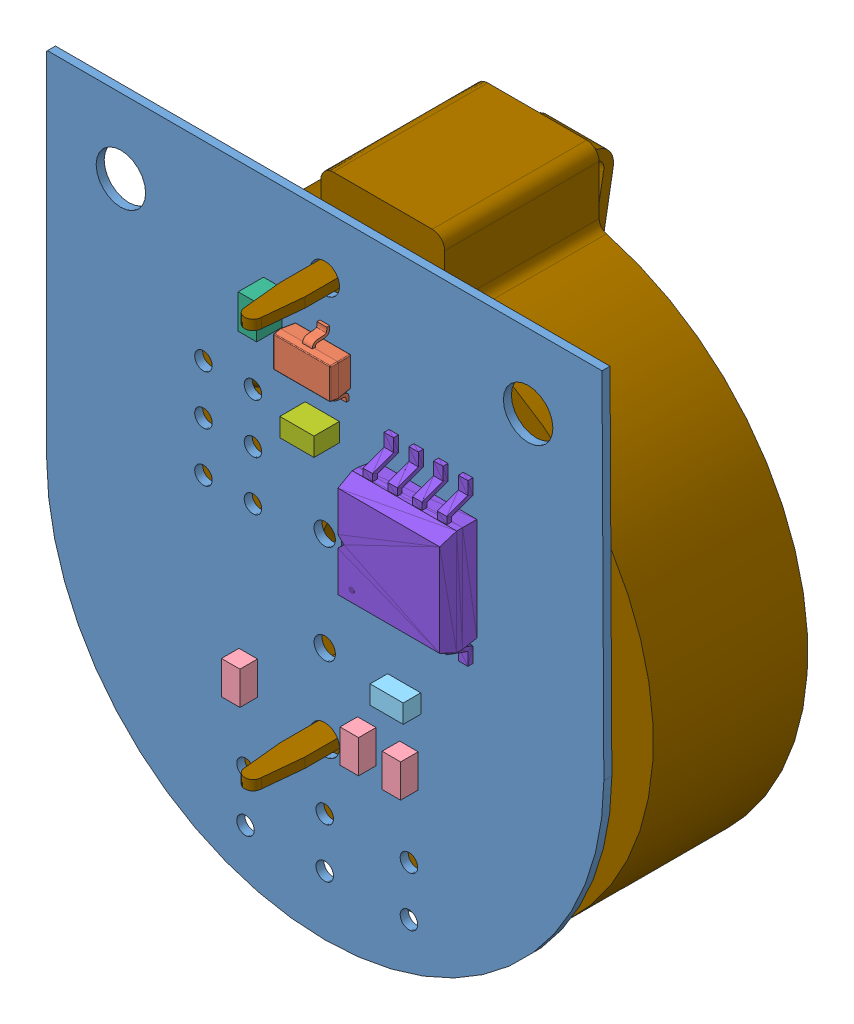
SolidWorks assembly Flashlight PCB 2, configuration Default. Lengths in mm.
Overall size (33.81 35.83 17.34).
27 component instances, 9 part files, 0 mates.
Components (placement in the parent):
- Board-1: Board [Default] at origin size (28.59 32.39 0.41)
- U1-1: U1 [Default] at origin size (3.01 2.91 1.23)
  - SOT23-3-1: SOT23-3 [Default] at (15.3909 26.7763 0) x (0 -1 0) z (0 0 1) size (2.91 3.01 1.23)
  - 4438511424-1: 4438511424 [Default] at (15.494 27.051 0) size (0.25 0.25 0.25)
    - Extruded-1: Extruded [Default] at origin size (0.25 0.25 0.25)
- R3-1: R3 [Default] at origin size (0.95 1.7 0.9)
  - 4438511040-1: 4438511040 [Default] at (19.685 10.656 0) size (0.95 1.7 0.9)
    - Extruded_2-1: Extruded_2 [Default] at origin size (0.95 1.7 0.9)
- R2-1: R2 [Default] at origin size (0.95 1.7 0.9)
  - 4438511040-1: 4438511040 [Default] at (17.526 10.656 0) size (0.95 1.7 0.9)
    - Extruded_2-1: Extruded_2 [Default] at origin size (0.95 1.7 0.9)
- R1-1: R1 [Default] at origin size (0.95 1.7 0.9)
  - 4438511040-1: 4438511040 [Default] at (11.442 10.656 0) size (0.95 1.7 0.9)
    - Extruded_2-1: Extruded_2 [Default] at origin size (0.95 1.7 0.9)
- R4-1: R4 [Default] at origin size (1.7 0.95 0.9)
  - 4438510848-1: 4438510848 [Default] at (19.443 13.716 0) size (1.7 0.95 0.9)
    - Extruded_3-1: Extruded_3 [Default] at origin size (1.7 0.95 0.9)
- C2-1: C2 [Default] at origin size (0.95 1.75 1.3)
  - 4438511232-1: 4438511232 [Default] at (12.7 27.748 0) size (0.95 1.75 1.3)
    - Extruded_4-1: Extruded_4 [Default] at origin size (0.95 1.75 1.3)
- C1-1: C1 [Default] at origin size (1.75 0.95 1.3)
  - 4438510656-1: 4438510656 [Default] at (15.24 23.684 0) size (1.75 0.95 1.3)
    - Extruded_5-1: Extruded_5 [Default] at origin size (1.75 0.95 1.3)
- ATTiny85-1: ATTiny85 [Default] at origin size (8.25 5.36 2.16)
  - 8S2-1: 8S2 [Default] at (20.8151 20.955 0) x (0 1 0) z (0 0 1) size (8.25 5.36 2.16)
- Imported-1: Imported [Default] at origin size (27.76 30.96 17.34)
  - keystone-PN1025-7-1: keystone-PN1025-7 [Default] at (15.3925 15.0498 -2.9515) x (1 0 0) z (0 1 0) size (27.76 17.34 30.96)
